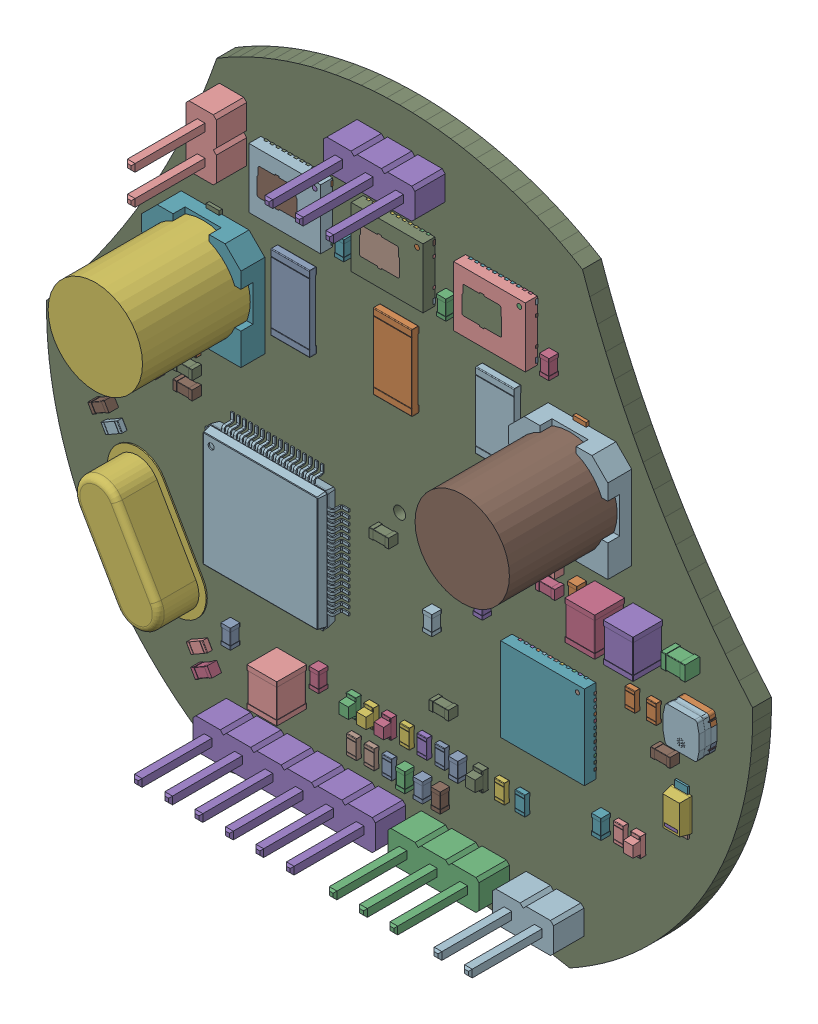
SolidWorks assembly MotorDriver, configuration Default. Lengths in mm.
Overall size (58.99 55.35 15.56).
139 component instances, 18 part files, 0 mates.
Components (placement in the parent):
- C_0603_1608Metric-1: C_0603_1608Metric [Default] at (70.1294 -150.0124 1.617) x (0 1 0) z (0 0 1) size (1.6 0.8 0.8)
  - SOLID-1: SOLID [Default] at origin size (1.6 0.8 0.8)
- R_2512_6332Metric-1: R_2512_6332Metric [Default] at (83.8708 -123.3932 1.617) x (0 -1 0) z (0 0 1) size (6.3 3.2 0.6)
  - SOLID-0-1: SOLID-0 [Default] at origin size (6.3 3.2 0.6)
- CSD88599Q5DC-1: CSD88599Q5DC [Default] at (92.4213 -115.5981 1.617) x (0 -1 0) z (-1 0 0) size (5 1.05 6)
  - COMPOUND-1: COMPOUND [Default] at origin size (5 1.05 6)
- PinHeader_1x06_P2.54mm_Vertical-1: PinHeader_1x06_P2.54mm_Vertical [Default] at (70.4088 -156.5148 1.617) x (0 1 0) z (0 0 1) size (2.54 15.24 11.54)
  - SOLID-1-1: SOLID-1 [Default] at origin size (2.54 15.24 11.54)
- CHEMI-HA0-1: CHEMI-HA0 [Default] at (68.5038 -124.5108 1.617) x (0 -1 0) z (0 0 1) size (8.99 8.31 10.06)
  - COMPOUND-2-1: COMPOUND-2 [Default] at origin size (8.99 8.31 10.06)
- C_0603_1608Metric-2: C_0603_1608Metric [Default] at (96.8248 -131.7498 1.617) x (-1 0 0) z (0 0 1) size (1.6 0.8 0.8)
  - SOLID-1: SOLID [Default] at origin size (1.6 0.8 0.8)
- C_0603_1608Metric-3: C_0603_1608Metric [Default] at (59.4965 -138.7567 1.617) x (-0.866025 -0.5 0) z (0 0 1) size (1.6 0.8 0.8)
  - SOLID-1: SOLID [Default] at origin size (1.6 0.8 0.8)
- PinHeader_1x02_P2.54mm_Vertical-1: PinHeader_1x02_P2.54mm_Vertical [Default] at (97.9982 -156.5148 1.617) x (0 -1 0) z (0 0 1) size (2.54 5.08 11.54)
  - SOLID-3-1: SOLID-3 [Default] at origin size (2.54 5.08 11.54)
- R_2512_6332Metric-2: R_2512_6332Metric [Default] at (75.3203 -123.3932 1.617) x (0 -1 0) z (0 0 1) size (6.3 3.2 0.6)
  - SOLID-0-1: SOLID-0 [Default] at origin size (6.3 3.2 0.6)
- R_0603_1608Metric-1: R_0603_1608Metric [Default] at (103.5558 -138.049 1.617) x (0 -1 0) z (0 0 1) size (1.6 0.8 0.45)
  - SOLID-4-1: SOLID-4 [Default] at origin size (1.6 0.8 0.45)
- C_0603_1608Metric-4: C_0603_1608Metric [Default] at (84.709 -153.1112 1.617) x (0 -1 0) z (0 0 1) size (1.6 0.8 0.8)
  - SOLID-1: SOLID [Default] at origin size (1.6 0.8 0.8)
- C_0603_1608Metric-5: C_0603_1608Metric [Default] at (68.0944 -153.6487 1.617) x (-0.866025 -0.5 0) z (0 0 1) size (1.6 0.8 0.8)
  - SOLID-1: SOLID [Default] at origin size (1.6 0.8 0.8)
- DIODE_SOD123LF_2P9X1P8_ONS-1: DIODE_SOD123LF_2P9X1P8_ONS [Default] at (107.5436 -144.145 1.617) x (0 -1 0) z (0 0 1) size (3.81 1.67 1)
  - COMPOUND-5-1: COMPOUND-5 [Default] at origin size (3.81 1.67 1)
- R_0603_1608Metric-2: R_0603_1608Metric [Default] at (60.452 -131.0386 1.617) size (1.6 0.8 0.45)
  - SOLID-4-1: SOLID-4 [Default] at origin size (1.6 0.8 0.45)
- PinHeader_1x02_P2.54mm_Vertical-2: PinHeader_1x02_P2.54mm_Vertical [Default] at (69.8246 -114.8384 1.617) x (-1 0 0) z (0 0 1) size (2.54 5.08 11.54)
  - SOLID-3-1: SOLID-3 [Default] at origin size (2.54 5.08 11.54)
- CHEMI-HA0-2: CHEMI-HA0 [Default] at (99.1616 -124.5108 1.617) x (0 -1 0) z (0 0 1) size (8.99 8.31 10.06)
  - COMPOUND-2-1: COMPOUND-2 [Default] at origin size (8.99 8.31 10.06)
- C_0603_1608Metric-6: C_0603_1608Metric [Default] at (88.138 -117.1956 1.617) x (0 -1 0) z (0 0 1) size (1.6 0.8 0.8)
  - SOLID-1: SOLID [Default] at origin size (1.6 0.8 0.8)
- C_0603_1608Metric-7: C_0603_1608Metric [Default] at (96.8248 -133.2738 1.617) size (1.6 0.8 0.8)
  - SOLID-1: SOLID [Default] at origin size (1.6 0.8 0.8)
- C_0603_1608Metric-8: C_0603_1608Metric [Default] at (91.186 -137.3124 1.617) x (0 -1 0) z (0 0 1) size (1.6 0.8 0.8)
  - SOLID-1: SOLID [Default] at origin size (1.6 0.8 0.8)
- R_0603_1608Metric-3: R_0603_1608Metric [Default] at (84.709 -150.1394 1.617) x (0 -1 0) z (0 0 1) size (1.6 0.8 0.45)
  - SOLID-4-1: SOLID-4 [Default] at origin size (1.6 0.8 0.45)
- R_0603_1608Metric-4: R_0603_1608Metric [Default] at (94.361 -150.1526 1.617) x (0 1 0) z (0 0 1) size (1.6 0.8 0.45)
  - SOLID-4-1: SOLID-4 [Default] at origin size (1.6 0.8 0.45)
- R_0603_1608Metric-5: R_0603_1608Metric [Default] at (80.2894 -153.1112 1.617) x (0 -1 0) z (0 0 1) size (1.6 0.8 0.45)
  - SOLID-4-1: SOLID-4 [Default] at origin size (1.6 0.8 0.45)
- C_0603_1608Metric-9: C_0603_1608Metric [Default] at (82.931 -136.4996 1.617) x (-1 0 0) z (0 0 1) size (1.6 0.8 0.8)
  - SOLID-1: SOLID [Default] at origin size (1.6 0.8 0.8)
- C_0603_1608Metric-10: C_0603_1608Metric [Default] at (63.4492 -133.985 1.617) x (-1 0 0) z (0 0 1) size (1.6 0.8 0.8)
  - SOLID-1: SOLID [Default] at origin size (1.6 0.8 0.8)
- C_0603_1608Metric-11: C_0603_1608Metric [Default] at (87.6554 -153.1112 1.617) x (0 -1 0) z (0 0 1) size (1.6 0.8 0.8)
  - SOLID-1: SOLID [Default] at origin size (1.6 0.8 0.8)
- C_0603_1608Metric-12: C_0603_1608Metric [Default] at (86.9696 -140.6144 1.617) x (0 1 0) z (0 0 1) size (1.6 0.8 0.8)
  - SOLID-1: SOLID [Default] at origin size (1.6 0.8 0.8)
- R_0603_1608Metric-6: R_0603_1608Metric [Default] at (87.6554 -150.1394 1.617) x (0 -1 0) z (0 0 1) size (1.6 0.8 0.45)
  - SOLID-4-1: SOLID-4 [Default] at origin size (1.6 0.8 0.45)
- C_0603_1608Metric-13: C_0603_1608Metric [Default] at (99.0854 -132.5118 1.617) x (0 1 0) z (0 0 1) size (1.6 0.8 0.8)
  - SOLID-1: SOLID [Default] at origin size (1.6 0.8 0.8)
- C_0805_2012Metric-1: C_0805_2012Metric [Default] at (107.95 -133.0706 1.617) x (-1 0 0) z (0 0 1) size (2 1.25 1.25)
  - SOLID-6-1: SOLID-6 [Default] at origin size (2 1.25 1.25)
- LED_0603_1608Metric-1: LED_0603_1608Metric [Default] at (83.2358 -150.1394 1.617) x (0 1 0) z (0 0 1) size (1.6 0.8 1.1)
  - SOLID-7-1: SOLID-7 [Default] at origin size (1.6 0.8 1.1)
- CSD88599Q5DC-2: CSD88599Q5DC [Default] at (75.3203 -115.5981 1.617) x (0 -1 0) z (-1 0 0) size (5 1.05 6)
  - COMPOUND-1: COMPOUND [Default] at origin size (5 1.05 6)
- C_0603_1608Metric-14: C_0603_1608Metric [Default] at (79.6036 -117.1702 1.617) x (0 -1 0) z (0 0 1) size (1.6 0.8 0.8)
  - SOLID-1: SOLID [Default] at origin size (1.6 0.8 0.8)
- R_0603_1608Metric-7: R_0603_1608Metric [Default] at (63.437 -131.0386 1.617) size (1.6 0.8 0.45)
  - SOLID-4-1: SOLID-4 [Default] at origin size (1.6 0.8 0.45)
- C_0603_1608Metric-15: C_0603_1608Metric [Default] at (66.5226 -132.5118 1.617) size (1.6 0.8 0.8)
  - SOLID-1: SOLID [Default] at origin size (1.6 0.8 0.8)
- R_0603_1608Metric-8: R_0603_1608Metric [Default] at (102.5906 -148.2852 1.617) x (0 -1 0) z (0 0 1) size (1.6 0.8 0.45)
  - SOLID-4-1: SOLID-4 [Default] at origin size (1.6 0.8 0.45)
- VLS3015CX-150M-1-1: VLS3015CX-150M-1 [Default] at (108.8898 -137.2362 1.617) x (0 1 0) z (1 0 0) size (3.01 1.5 3.01)
  - COMPOUND-8-1: COMPOUND-8 [Default] at origin size (3.01 1.5 3.01)
- LED_0603_1608Metric-2: LED_0603_1608Metric [Default] at (90.8861 -150.1326 1.617) x (0 1 0) z (0 0 1) size (1.6 0.8 1.1)
  - SOLID-7-1: SOLID-7 [Default] at origin size (1.6 0.8 1.1)
- R_0603_1608Metric-9: R_0603_1608Metric [Default] at (67.3578 -152.3729 1.617) x (-0.866025 -0.5 0) z (0 0 1) size (1.6 0.8 0.45)
  - SOLID-4-1: SOLID-4 [Default] at origin size (1.6 0.8 0.45)
- C_0603_1608Metric-16: C_0603_1608Metric [Default] at (106.4514 -140.6144 1.617) size (1.6 0.8 0.8)
  - SOLID-1: SOLID [Default] at origin size (1.6 0.8 0.8)
- LQFP-64_10x10mm_P0.5mm-1: LQFP-64_10x10mm_P0.5mm [Default] at (73.7108 -140.2334 1.617) size (12 12 1.5)
  - SOLID-9-1: SOLID-9 [Default] at origin size (12 12 1.5)
- C_0603_1608Metric-17: C_0603_1608Metric [Default] at (89.1286 -150.1526 1.617) x (0 -1 0) z (0 0 1) size (1.6 0.8 0.8)
  - SOLID-1: SOLID [Default] at origin size (1.6 0.8 0.8)
- CSD88599Q5DC-3: CSD88599Q5DC [Default] at (83.8708 -115.5981 1.617) x (0 -1 0) z (-1 0 0) size (5 1.05 6)
  - COMPOUND-1: COMPOUND [Default] at origin size (5 1.05 6)
- C_0603_1608Metric-18: C_0603_1608Metric [Default] at (96.7486 -117.1956 1.617) x (0 -1 0) z (0 0 1) size (1.6 0.8 0.8)
  - SOLID-1: SOLID [Default] at origin size (1.6 0.8 0.8)
- PinHeader_1x03_P2.54mm_Vertical-1: PinHeader_1x03_P2.54mm_Vertical [Default] at (86.4108 -109.1692 1.617) x (0 -1 0) z (0 0 1) size (2.54 7.62 11.54)
  - SOLID-10-1: SOLID-10 [Default] at origin size (2.54 7.62 11.54)
- R_0603_1608Metric-10: R_0603_1608Metric [Default] at (92.6435 -150.1526 1.617) x (0 1 0) z (0 0 1) size (1.6 0.8 0.45)
  - SOLID-4-1: SOLID-4 [Default] at origin size (1.6 0.8 0.45)
- C_0603_1608Metric-19: C_0603_1608Metric [Default] at (101.092 -148.2976 1.617) x (0 -1 0) z (0 0 1) size (1.6 0.8 0.8)
  - SOLID-1: SOLID [Default] at origin size (1.6 0.8 0.8)
- R_0603_1608Metric-11: R_0603_1608Metric [Default] at (81.7626 -153.1112 1.617) x (0 -1 0) z (0 0 1) size (1.6 0.8 0.45)
  - SOLID-4-1: SOLID-4 [Default] at origin size (1.6 0.8 0.45)
- C_0603_1608Metric-20: C_0603_1608Metric [Default] at (87.9348 -146.4564 1.617) size (1.6 0.8 0.8)
  - SOLID-1: SOLID [Default] at origin size (1.6 0.8 0.8)
- LED_0603_1608Metric-3: LED_0603_1608Metric [Default] at (104.0638 -148.2853 1.617) x (0 -1 0) z (0 0 1) size (1.6 0.8 1.1)
  - SOLID-7-1: SOLID-7 [Default] at origin size (1.6 0.8 1.1)
- C_0603_1608Metric-21: C_0603_1608Metric [Default] at (66.5226 -133.985 1.617) size (1.6 0.8 0.8)
  - SOLID-1: SOLID [Default] at origin size (1.6 0.8 0.8)
- R_0603_1608Metric-12: R_0603_1608Metric [Default] at (60.2331 -140.0325 1.617) x (-0.866025 -0.5 0) z (0 0 1) size (1.6 0.8 0.45)
  - SOLID-4-1: SOLID-4 [Default] at origin size (1.6 0.8 0.45)
- C_0603_1608Metric-22: C_0603_1608Metric [Default] at (86.1822 -153.1112 1.617) x (0 -1 0) z (0 0 1) size (1.6 0.8 0.8)
  - SOLID-1: SOLID [Default] at origin size (1.6 0.8 0.8)
- R_0603_1608Metric-13: R_0603_1608Metric [Default] at (105.3338 -138.049 1.617) x (0 -1 0) z (0 0 1) size (1.6 0.8 0.45)
  - SOLID-4-1: SOLID-4 [Default] at origin size (1.6 0.8 0.45)
- PinHeader_1x03_P2.54mm_Vertical-2: PinHeader_1x03_P2.54mm_Vertical [Default] at (91.7702 -156.5148 1.617) x (0 -1 0) z (0 0 1) size (2.54 7.62 11.54)
  - SOLID-10-1: SOLID-10 [Default] at origin size (2.54 7.62 11.54)
- C_1210_3225Metric-1: C_1210_3225Metric [Default] at (101.4222 -132.9436 1.617) x (0 1 0) z (0 0 1) size (3.2 2.5 2.5)
  - SOLID-11-1: SOLID-11 [Default] at origin size (3.2 2.5 2.5)
- C_1210_3225Metric-2: C_1210_3225Metric [Default] at (104.6226 -132.9436 1.617) x (0 1 0) z (0 0 1) size (3.2 2.5 2.5)
  - SOLID-11-1: SOLID-11 [Default] at origin size (3.2 2.5 2.5)
- Part31-1: Part31 [Default] at (63.6748 -145.9937 1.617) x (-0.5 0.866025 0) z (0.866025 0.5 0) size (11.5 9 5)
  - SOLID-12-1: SOLID-12 [Default] at origin size (11.5 9 5)
- DRV8323RSRGZR-1: DRV8323RSRGZR [Default] at (96.8104 -142.12 1.617) x (0 -1 0) z (-1 0 0) size (7 1 7)
  - COMPOUND-13-1: COMPOUND-13 [Default] at origin size (7 1 7)
- C_1210_3225Metric-3: C_1210_3225Metric [Default] at (74.8538 -151.0538 1.617) x (0 1 0) z (0 0 1) size (3.2 2.5 2.5)
  - SOLID-11-1: SOLID-11 [Default] at origin size (3.2 2.5 2.5)
- C_0603_1608Metric-23: C_0603_1608Metric [Default] at (63.4492 -132.5118 1.617) size (1.6 0.8 0.8)
  - SOLID-1: SOLID [Default] at origin size (1.6 0.8 0.8)
- R_2512_6332Metric-3: R_2512_6332Metric [Default] at (92.4213 -123.3932 1.617) x (0 -1 0) z (0 0 1) size (6.3 3.2 0.6)
  - SOLID-0-1: SOLID-0 [Default] at origin size (6.3 3.2 0.6)
- R_0603_1608Metric-14: R_0603_1608Metric [Default] at (83.2358 -153.1112 1.617) x (0 -1 0) z (0 0 1) size (1.6 0.8 0.45)
  - SOLID-4-1: SOLID-4 [Default] at origin size (1.6 0.8 0.45)
- R_0603_1608Metric-15: R_0603_1608Metric [Default] at (66.5104 -131.0386 1.617) x (-1 0 0) z (0 0 1) size (1.6 0.8 0.45)
  - SOLID-4-1: SOLID-4 [Default] at origin size (1.6 0.8 0.45)
- LED_0603_1608Metric-4: LED_0603_1608Metric [Default] at (80.2894 -150.1394 1.617) x (0 1 0) z (0 0 1) size (1.6 0.8 1.1)
  - SOLID-7-1: SOLID-7 [Default] at origin size (1.6 0.8 1.1)
- C_0603_1608Metric-24: C_0603_1608Metric [Default] at (77.4954 -149.4666 1.617) x (0 1 0) z (0 0 1) size (1.6 0.8 0.8)
  - SOLID-1: SOLID [Default] at origin size (1.6 0.8 0.8)
- R_0603_1608Metric-16: R_0603_1608Metric [Default] at (86.1822 -150.1394 1.617) x (0 -1 0) z (0 0 1) size (1.6 0.8 0.45)
  - SOLID-4-1: SOLID-4 [Default] at origin size (1.6 0.8 0.45)
- LED_0603_1608Metric-5: LED_0603_1608Metric [Default] at (81.7626 -150.1394 1.617) x (0 1 0) z (0 0 1) size (1.6 0.8 1.1)
  - SOLID-7-1: SOLID-7 [Default] at origin size (1.6 0.8 1.1)
- C_0603_1608Metric-25: C_0603_1608Metric [Default] at (78.74 -136.2072 -0.05) x (0 1 0) z (0 0 -1) size (1.6 0.8 0.8)
  - SOLID-1: SOLID [Default] at origin size (1.6 0.8 0.8)
- TSSOP-14_4.4x5mm_P0.65mm-1: TSSOP-14_4.4x5mm_P0.65mm [Default] at (83.82 -134.62 -0.05) x (-1 0 0) z (0 0 -1) size (6.4 5 1)
  - SOLID-14-1: SOLID-14 [Default] at origin size (6.4 5 1)
- _autosave-MotorDriver PCB-1: _autosave-MotorDriver PCB [Default] at origin size (58.99 55.35 1.57)
